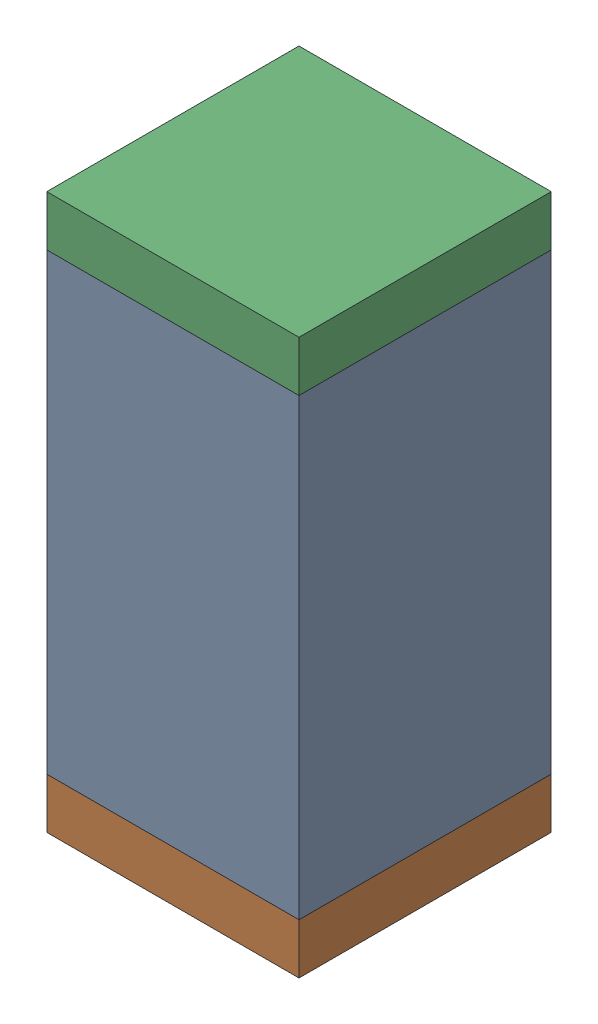
SolidWorks assembly C41, configuration Default. Lengths in mm.
Overall size (0.5 1.1 0.5).
6 component instances, 2 part files, 0 mates.
Components (placement in the parent):
- 791586336-1: 791586336 [Default] at (125.9 35.4 0) size (0.5 0.9 0.5)
  - Extruded_8-1: Extruded_8 [Default] at origin size (0.5 0.9 0.5)
- 810157360-1: 810157360 [Default] at (125.9 34.9 0) size (0.5 0.1 0.5)
  - Extruded_9-1: Extruded_9 [Default] at origin size (0.5 0.1 0.5)
- 810157360-2: 810157360 [Default] at (125.9 35.9 0) size (0.5 0.1 0.5)
  - Extruded_9-1: Extruded_9 [Default] at origin size (0.5 0.1 0.5)
